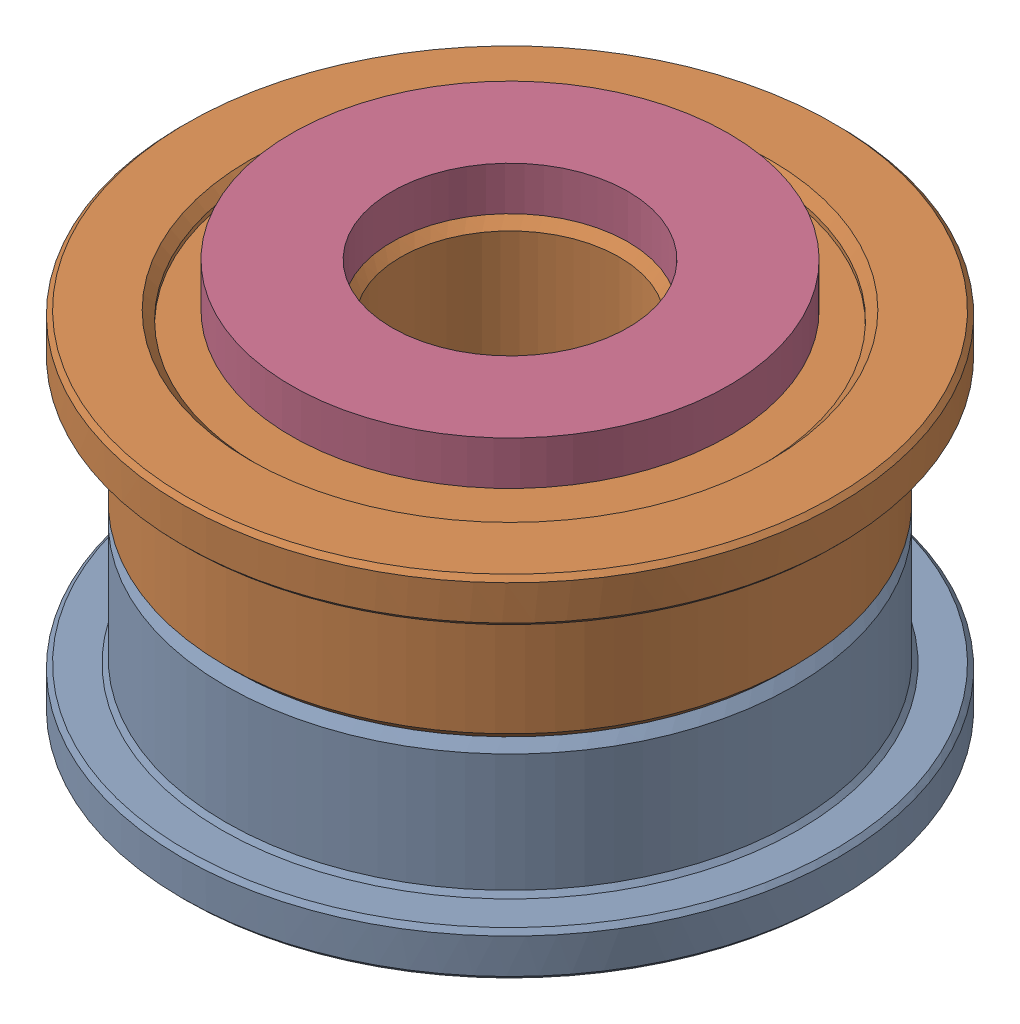
SolidWorks assembly Idler Pulley Assembly v3_5, configuration Default. Lengths in mm.
Overall size (15 10 15).
4 component instances, 3 part files, 0 mates.
Components (placement in the parent):
- F695-2RS v1 (1)-1: F695-2RS v1 (1) [Default] at origin size (15 4 15)
- F695-2RS v1 (2)-1: F695-2RS v1 (2) [Default] at (0 8 0) x (-1 0 0) z (0 0 1) size (15 4 15)
- M5 1mm Spacer-1: M5 1mm Spacer [Default] at (0 0 -350) size (10 1 10)
- M5 1mm Spacer-2: M5 1mm Spacer [Default] at (0 9 -350) size (10 1 10)
